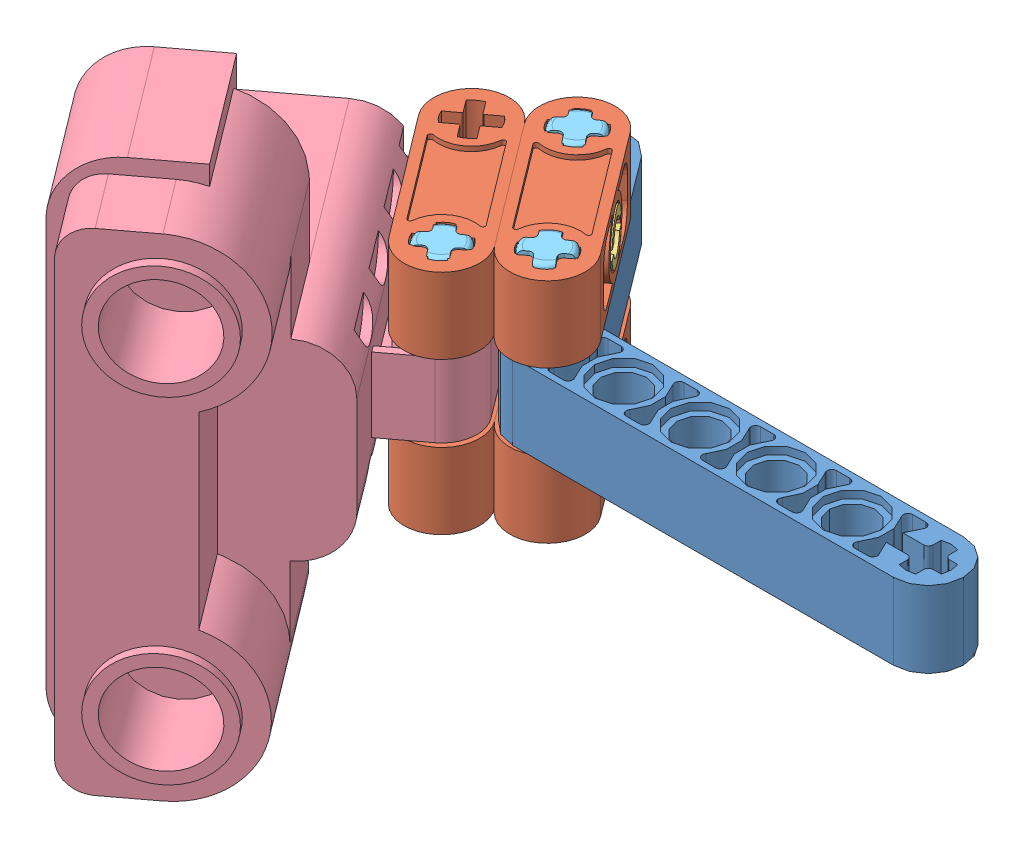
SolidWorks assembly Mantis step 18, configuration Default. Lengths in mm.
Overall size (84.72 55.29 62.72).
12 component instances, 6 part files, 29 mates.
Components (placement in the parent):
- beam_angle-1: beam_angle [Default] at (-9.7075 -7.1115 10.0876) size (62.29 8.06 26.73)
- crossblock double-1: crossblock double [Predeterminado] at (-20.9111 4.9535 8.5131) x (0.601815 0 0.798636) z (0 1 0) size (24 8 8)
- crossblock double-2: crossblock double [Predeterminado] at (-20.9111 -11.1115 8.5131) x (0.601815 0 0.798636) z (0 -1 0) size (24 8 8)
- crossblock double-3: crossblock double [Predeterminado] at (-14.522 4.9535 3.6986) x (0.601815 0 0.798636) z (0 -1 0) size (24 8 8)
- crossblock double-4: crossblock double [Predeterminado] at (-14.522 -11.1115 3.6986) x (0.601815 0 0.798636) z (0 1 0) size (24 8 8)
- conn-1: conn [Default] at (-17.6766 4.9535 6.0757) x (0.601815 0 0.798636) z (0 -1 0) size (6.15 16.1 6.07)
- conn-2: conn [Default] at (-17.6766 -11.1115 6.0757) x (0.601815 0 0.798636) z (0 1 0) size (6.15 16.1 6.07)
- sensor_sonar-1: sensor_sonar [Default] at (-27.4904 -2.9715 25.5541) x (0 -1 0) z (0.798636 0 -0.601815) size (55.29 42.67 31.61)
- axle_3-1: axle_3 [Default] at (-16.0965 -15.0908 14.9022) x (-0.793645 0 0.608381) z (-0.608381 0 -0.793645) size (4.78 24.27 4.78)
- axle_3-2: axle_3 [Default] at (-9.7075 -14.8289 10.0876) x (0.789491 0 -0.613762) z (0.613762 0 0.789491) size (4.78 24.27 4.78)
- axle_3-3: axle_3 [Default] at (-19.3365 -15.0105 -2.6905) x (0.794342 0 -0.607471) z (0.607471 0 0.794342) size (4.78 24.27 4.78)
- socket-1: socket [Default] at (-39.3512 -2.9715 7.571) x (0 1 0) z (0.601815 0 0.798636) size (12.5 15 12.59)
Mates (geometry in assembly coordinates):
- Parallel1: parallel aligned: plane of beam_angle-1 through (-27.5279 -7.2728 -7.4129) normal (-0.798636 0 0.601815); plane of crossblock double-3 through (-22.531 0.9535 -0.2833) normal (-0.798636 0 0.601815)
- Coincident2: coincident anti-aligned: plane of beam_angle-1 through (-29.2291 0.9535 14.3223) normal (0 1 0); plane of crossblock double-3 through (-9.7075 0.9535 10.0876) normal (0 -1 0)
- Parallel3: parallel aligned: plane of beam_angle-1 through (-27.5279 -7.2728 -7.4129) normal (-0.798636 0 0.601815); plane of crossblock double-4 through (-22.531 -7.1115 -0.2833) normal (-0.798636 0 0.601815)
- Coincident5: coincident anti-aligned: plane of beam_angle-1 through (-29.2291 -7.1115 14.3223) normal (0 -1 0); plane of crossblock double-4 through (-9.7075 -7.1115 10.0876) normal (0 1 0)
- Concentric3: concentric aligned: cylinder of crossblock double-2 through (-17.7165 -11.1115 6.1058) axis (-0.798636 0 0.601815) radius 2.5; cylinder of crossblock double-4 through (-17.3172 -11.1115 5.8049) axis (-0.798636 0 0.601815) radius 2.75
- Coincident6: coincident aligned: plane of crossblock double-2 through (-16.0965 -15.1115 14.9022) normal (0 -1 0); plane of crossblock double-4 through (-9.7075 -15.1115 10.0876) normal (0 -1 0)
- Coincident7: coincident anti-aligned: plane of crossblock double-2 through (-22.531 -15.1115 -0.2833) normal (0.798636 0 -0.601815); plane of crossblock double-4 through (-22.531 -7.1115 -0.2833) normal (-0.798636 0 0.601815)
- Concentric4: concentric anti-aligned: cylinder of crossblock double-1 through (-24.1056 4.9535 10.9203) axis (0.798636 0 -0.601815) radius 2.5; cylinder of crossblock double-3 through (-17.3172 4.9535 5.8049) axis (-0.798636 0 0.601815) radius 2.75
- Coincident8: coincident aligned: plane of crossblock double-1 through (-16.0965 8.9535 14.9022) normal (0 1 0); plane of crossblock double-3 through (-9.7075 8.9535 10.0876) normal (0 1 0)
- Coincident9: coincident anti-aligned: plane of crossblock double-1 through (-22.531 8.9535 -0.2833) normal (0.798636 0 -0.601815); plane of crossblock double-3 through (-22.531 0.9535 -0.2833) normal (-0.798636 0 0.601815)
- Concentric6: concentric anti-aligned: cylinder of crossblock double-1 through (-24.1056 4.9535 10.9203) axis (0.798636 0 -0.601815) radius 2.5; cylinder of conn-1 through (-11.9259 4.9535 1.7423) axis (-0.798636 0 0.601815) radius 2.39
- Concentric7: concentric anti-aligned: cylinder of conn-2 through (-23.3168 -11.1115 10.326) axis (0.798636 0 -0.601815) radius 2.39; cylinder of crossblock double-2 through (-17.7165 -11.1115 6.1058) axis (-0.798636 0 0.601815) radius 2.5
- Concentric10: concentric anti-aligned: cylinder of crossblock double-4 through (-19.3365 -7.1115 -2.6905) axis (0 -1 0) radius 2.5; cylinder of axle_3-3 through (-19.3365 -14.5105 -2.6905) axis (0 1 0) radius 2.39
- Concentric12: concentric anti-aligned: cylinder of crossblock double-4 through (-9.7075 -7.1115 10.0876) axis (0 -1 0) radius 2.5; cylinder of axle_3-2 through (-9.7075 -14.3289 10.0876) axis (0 1 0) radius 2.39
- Lock5: lock: unknown of ?; unknown of ?
- Lock7: lock: unknown of ?; unknown of ?
- Coincident13: coincident anti-aligned: plane of socket-1 through (-37.8183 3.2785 22.0675) normal (0 1 0); plane of sensor_sonar-1 through (-37.8995 3.2785 22.4417) normal (0 -1 0)
- Coincident14: coincident anti-aligned: plane of sensor_sonar-1 through (-25.6883 3.0085 13.2399) normal (-0.798636 0 0.601815); plane of socket-1 through (-25.8388 -9.2215 13.0403) normal (0.798636 0 -0.601815)
- Coincident15: coincident anti-aligned: plane of sensor_sonar-1 through (-25.5992 3.5285 12.8597) normal (-0.601815 0 -0.798636); plane of socket-1 through (-37.8183 -9.2215 22.0675) normal (0.601815 0 0.798636)
- Concentric13: concentric anti-aligned: cylinder of sensor_sonar-1 through (-16.0965 0.1385 14.9022) axis (0 -1 0) radius 2.39; circle of crossblock double-2
- Parallel4: parallel anti-aligned: plane of beam_angle-1 through (-27.5279 -7.2728 -7.4129) normal (-0.798636 0 0.601815); plane of sensor_sonar-1 through (-12.9315 1.1105 12.9211) normal (0.798636 0 -0.601815)
- Coincident17: coincident anti-aligned: plane of crossblock double-1 through (-16.0965 0.9535 14.9022) normal (0 -1 0); plane of sensor_sonar-1 through (-32.2795 0.9535 1.6518) normal (0 1 0)
- Concentric14: concentric anti-aligned: cylinder of crossblock double-1 through (-16.0965 8.9535 14.9022) axis (0 -1 0) radius 2.5; cylinder of axle_3-1 through (-16.0965 -14.5908 14.9022) axis (0 1 0) radius 2.39
- Lock8: lock: unknown of ?; unknown of ?
- Concentric15: concentric aligned: circle of beam_angle-1; circle of crossblock double-4
- Parallel5: parallel anti-aligned: plane of conn-1 through (-17.704 4.9535 6.0964) normal (0 -1 0); plane of assembly through (0 0 0) normal (0 1 0)
- Parallel7: parallel aligned: plane of conn-2 through (-17.5387 -11.1115 5.9718) normal (0 1 0); plane of assembly through (0 0 0) normal (0 1 0)
- Coincident21: coincident aligned: plane of crossblock double-2 through (-28.9201 -15.1115 4.5313) normal (-0.798636 0 0.601815); plane of conn-2 through (-25.6706 -8.4595 8.8435) normal (-0.798636 0 0.601815)
- Coincident22: coincident aligned: plane of crossblock double-1 through (-28.9201 8.9535 4.5313) normal (-0.798636 0 0.601815); plane of conn-1 through (-25.6706 2.3015 8.8435) normal (-0.798636 0 0.601815)
